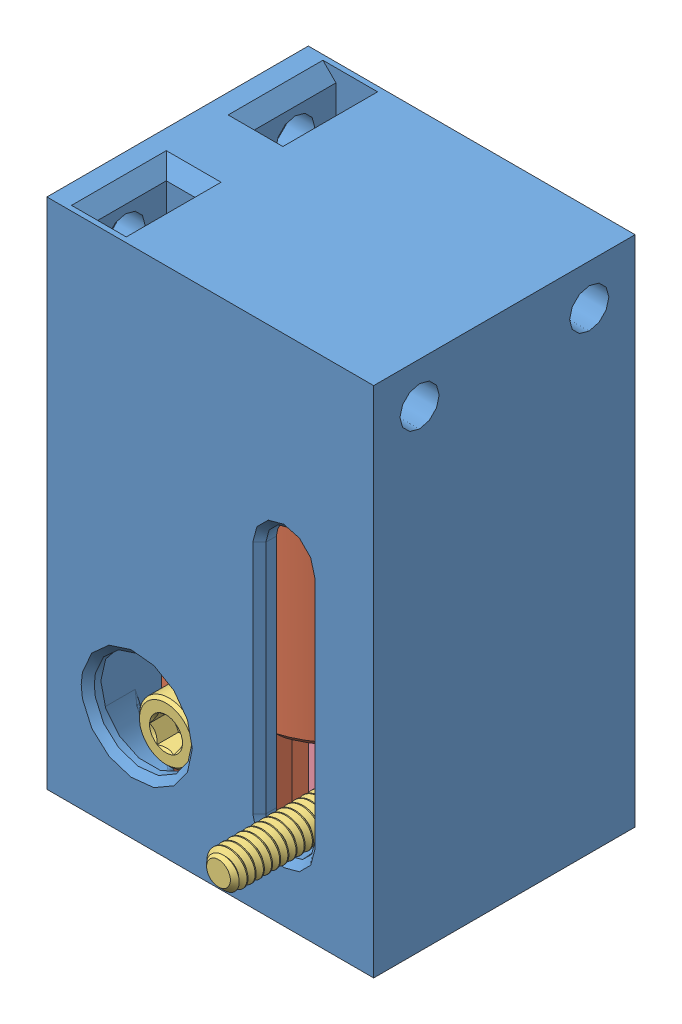
SolidWorks assembly PEN ADAPTER, configuration Default. Lengths in mm.
Overall size (31.75 49.85 38.77).
6 component instances, 4 part files, 13 mates.
Components (placement in the parent):
- PEN SLEEVE-1: PEN SLEEVE [Default] at (-10.618 -30.626 0) size (31.75 49.85 25.4)
- PEN ADAPTER-1: PEN ADAPTER [Default] at (-10.618 -29.356 0) x (0 0 1) z (-1 0 0) size (19.05 31.75 22.23)
- 92196A153-1: 92196A153 [92196A153] at (-3.4743 -23.006 19.05) x (0.974678 0.223614 0) z (0 0 1) size (5.74 5.74 29.4)
- 94855A201-1: 94855A201 [94855A201] at (-3.4743 -23.006 4.9609) x (1 0 0) z (0 1 0) size (7.94 3.39 7.94)
- 94855A201-2: 94855A201 [94855A201] at (-17.7618 -23.006 -4.9609) x (-1 0 0) z (0 1 0) size (7.94 3.39 7.94)
- 92196A153-2: 92196A153 [92196A153] at (-17.7618 -23.006 -19.05) x (0.050965 0.9987 0) z (0 0 -1) size (5.74 5.74 29.4)
Mates (geometry in assembly coordinates):
- Concentric1: concentric aligned: cylinder of PEN SLEEVE-1 through (-10.618 7.474 0) axis (0 -1 0) radius 10.4775; cylinder of PEN ADAPTER-1 through (-10.618 2.394 0) axis (0 -1 0) radius 9.525
- Parallel1: parallel anti-aligned: plane of PEN SLEEVE-1 through (-22.683 7.474 0) normal (1 0 0); plane of PEN ADAPTER-1 through (-21.7305 -10.306 0) normal (-1 0 0)
- Concentric2: concentric aligned: cylinder of PEN ADAPTER-1 through (-3.4743 -23.006 9.525) axis (0 0 -1) radius 1.905; circle of 92196A153-1
- Coincident1: coincident anti-aligned: plane of PEN ADAPTER-1 through (-10.618 -10.306 -6.35) normal (0 0 -1); plane of 92196A153-1 through (-3.4743 -23.006 -6.35) normal (0 0 1)
- Concentric3: concentric anti-aligned: circle of 92196A153-1; circle of 94855A201-1
- Coincident2: coincident anti-aligned: plane of PEN ADAPTER-1 through (-7.443 -19.0373 9.525) normal (0 -1 0); plane of 94855A201-1 through (-7.443 -19.0373 3.5719) normal (0 1 0)
- Coincident3: coincident: plane of PEN ADAPTER-1 through (-10.618 -29.356 3.5719) normal (0 0 1); point of 94855A201-1
- Concentric4: concentric anti-aligned: circle of 94855A201-2; circle of 92196A153-2
- Concentric5: concentric aligned: circle of PEN ADAPTER-1; circle of 92196A153-2
- Coincident4: coincident anti-aligned: plane of PEN ADAPTER-1 through (-17.7175 2.394 6.35) normal (0 0 1); plane of 92196A153-2 through (-17.7618 -23.006 6.35) normal (0 0 -1)
- Coincident5: coincident anti-aligned: plane of PEN ADAPTER-1 through (-13.793 -19.0373 -9.525) normal (0 -1 0); plane of 94855A201-2 through (-13.793 -19.0373 -3.5719) normal (0 1 0)
- Coincident6: coincident: plane of PEN ADAPTER-1 through (-10.618 -29.356 -3.5719) normal (0 0 -1); point of 94855A201-2
- LimitDistance2: limit distance = 1.27 mm aligned: plane of PEN ADAPTER-1 through (-10.618 -29.356 0) normal (0 -1 0); plane of PEN SLEEVE-1 through (-10.618 -30.626 0) normal (0 -1 0)
